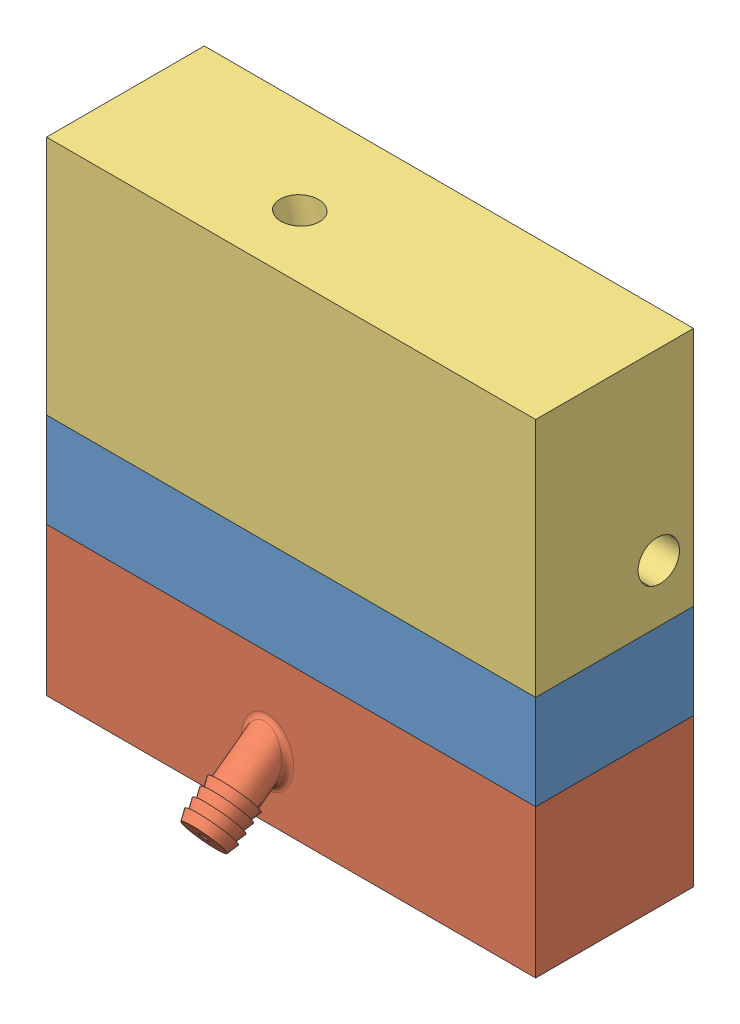
SolidWorks assembly TestFitTorusCascaded, configuration Default. Lengths in mm.
Overall size (155 153.27 73.86).
3 component instances, 3 part files, 8 mates.
Components (placement in the parent):
- AdjustableMidPiece-1: AdjustableMidPiece [Default] at (50.3326 32.2963 66.4236) size (155 30 50)
- Bottom Section-1: Bottom Section [Default] at (50.3326 105.2963 66.4236) size (155 47 73.86)
- Torus Master-1: Torus Master [Default] at (50.3326 98.57 66.4236) size (155 76.27 50)
Mates (geometry in assembly coordinates):
- Concentric1: concentric aligned: cylinder of AdjustableMidPiece-1 through (50.3326 62.2963 66.4236) axis (0 -1 0) radius 9; cylinder of Bottom Section-1 through (50.3326 74.2963 66.4236) axis (0 -1 0) radius 9
- Concentric2: concentric aligned: cylinder of AdjustableMidPiece-1 through (50.3326 62.2963 66.4236) axis (0 -1 0) radius 9; cylinder of Torus Master-1 through (50.3326 72.57 66.4236) axis (0 -1 0) radius 9
- Coincident5: coincident anti-aligned: plane of AdjustableMidPiece-1 through (50.3326 62.2963 66.4236) normal (0 1 0); plane of Torus Master-1 through (50.3326 62.2963 66.4236) normal (0 -1 0)
- Coincident6: coincident aligned: plane of AdjustableMidPiece-1 through (-19.6674 62.2963 86.4236) normal (0 0 1); plane of Bottom Section-1 through (50.3326 105.2963 86.4236) normal (0 0 1)
- Coincident7: coincident aligned: plane of AdjustableMidPiece-1 through (-19.6674 62.2963 36.4236) normal (-1 0 0); plane of Bottom Section-1 through (-19.6674 145.2963 36.4236) normal (-1 0 0)
- Parallel1: parallel anti-aligned: plane of Torus Master-1 through (50.3326 62.2963 66.4236) normal (0 -1 0); plane of AdjustableMidPiece-1 through (50.3326 62.2963 66.4236) normal (0 1 0)
- Coincident10: coincident aligned: plane of AdjustableMidPiece-1 through (-19.6674 62.2963 36.4236) normal (-1 0 0); plane of Torus Master-1 through (-19.6674 138.57 36.4236) normal (-1 0 0)
- Coincident11: coincident aligned: plane of AdjustableMidPiece-1 through (-19.6674 62.2963 86.4236) normal (0 0 1); plane of Torus Master-1 through (50.3326 98.57 86.4236) normal (0 0 1)
